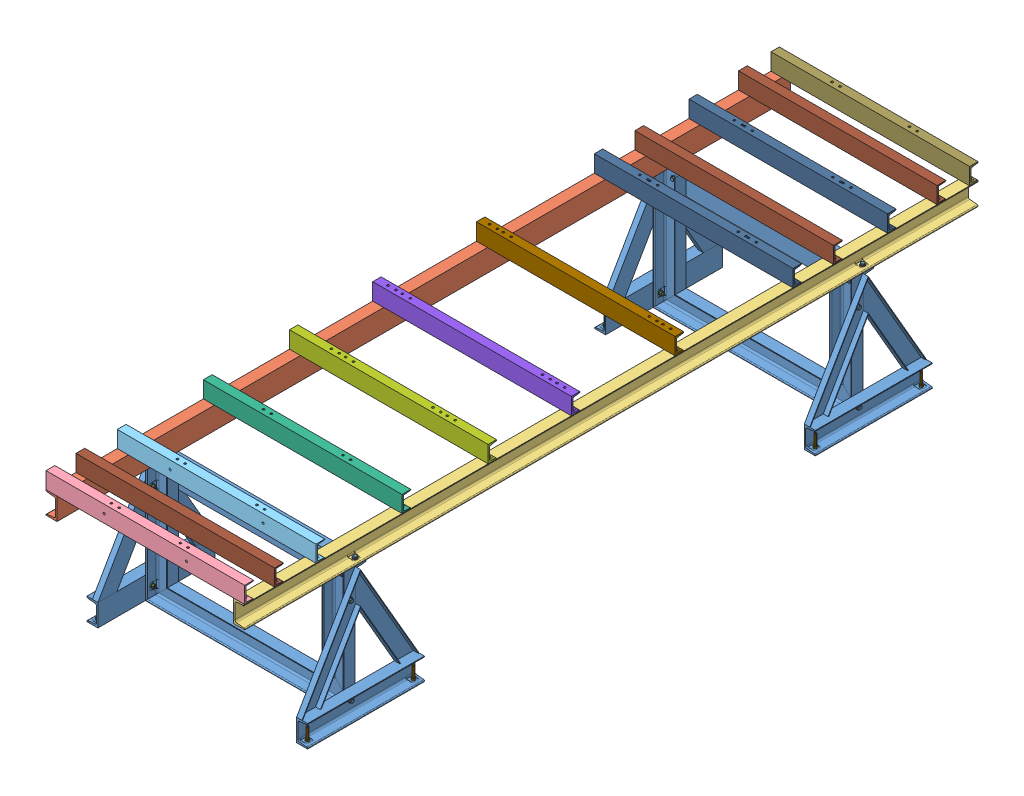
SolidWorks assembly MainJig, configuration Default. Lengths in mm.
Overall size (1000 753.95 3322.05).
208 component instances, 16 part files, 46 mates.
Components (placement in the parent):
- MainJigLegs-1: MainJigLegs [Default<As Machined>] at origin size (1000 560 530)
- MainJigLegs-2: MainJigLegs [Default<As Machined>] at (0 0 2300) size (1000 560 530)
- MainJigLongRailRight-1: MainJigLongRailRight [Default<As Machined>] at (-400 50 2270) x (0 0 -1) z (1 0 0) size (3322 100 50)
- MainJigLongRailLeft-1: MainJigLongRailLeft [Default<As Machined>] at (400 50 2270) x (0 0 -1) z (1 0 0) size (3322 100 50)
- MainJigCrossRailA-1: MainJigCrossRailA [Default<As Machined>] at (0 137.5 2800) size (900 75 40)
- MainJigCrossRailC-2: MainJigCrossRailC [Default<As Machined>] at (0 137.5 2477) size (900 75 40)
- MainJigCrossRailD-3: MainJigCrossRailD [Default<As Machined>] at (0 137.5 2087.1) size (900 75 40)
- MainJigCrossRailE-4: MainJigCrossRailE [Default<As Machined>] at (0 138.1 1697) size (900 76.2 38.05)
- MainJigCrossRailF-5: MainJigCrossRailF [Default<As Machined>] at (0 138.1 1320) size (900 76.2 38.05)
- MainJigCrossRailG-6: MainJigCrossRailG [Default<As Machined>] at (0 138.1 850) size (900 76.2 38.05)
- MainJigCrossRailH-7: MainJigCrossRailH [Default<As Machined>] at (0 138.1 316.2) size (900 76.2 38.05)
- MainJigCrossRail-8: MainJigCrossRail [Default<As Machined>] at (0 137.5 2664.3) size (900 75 40)
- MainJigCrossRail-9: MainJigCrossRail [Default<As Machined>] at (0 137.5 132.6) size (900 75 40)
- MainJigCrossRailH-10: MainJigCrossRailH [Default<As Machined>] at (0 138.1 -112.5) size (900 76.2 38.05)
- MainJigCrossRail-11: MainJigCrossRail [Default<As Machined>] at (0 137.5 -336.9) size (900 75 40)
- MainJigCrossRailL-12: MainJigCrossRailL [Default<As Machined>] at (0 138.1 -484) size (900 76.2 38.05)
- Flat Washer Type A Narrow_AI-36: Flat Washer Type A Narrow_AI [Preferred Narrow FW 0.375] at (425 105 2780) x (0 -1 0) z (0 0 1) size (1.65 20.62 20.62)
- Flat Washer Type A Narrow_AI-37: Flat Washer Type A Narrow_AI [Preferred Narrow FW 0.375] at (425 104 2457) x (0 -1 0) z (0 0 1) size (1.65 20.62 20.62)
- Flat Washer Type A Narrow_AI-38: Flat Washer Type A Narrow_AI [Preferred Narrow FW 0.375] at (425 105 2067.1) x (0 -1 0) z (0 0 1) size (1.65 20.62 20.62)
- Flat Washer Type A Narrow_AI-39: Flat Washer Type A Narrow_AI [Preferred Narrow FW 0.375] at (425 105 1677) x (0 -1 0) z (0 0 1) size (1.65 20.62 20.62)
- Flat Washer Type A Narrow_AI-40: Flat Washer Type A Narrow_AI [Preferred Narrow FW 0.375] at (425 105 1300) x (0 -1 0) z (0 0 1) size (1.65 20.62 20.62)
- Flat Washer Type A Narrow_AI-41: Flat Washer Type A Narrow_AI [Preferred Narrow FW 0.375] at (425 105 830) x (0 -1 0) z (0 0 1) size (1.65 20.62 20.62)
- Flat Washer Type A Narrow_AI-42: Flat Washer Type A Narrow_AI [Preferred Narrow FW 0.375] at (425 105 2644.3) x (0 -1 0) z (0 0 1) size (1.65 20.62 20.62)
- Flat Washer Type A Narrow_AI-43: Flat Washer Type A Narrow_AI [Preferred Narrow FW 0.375] at (425 105 296.2) x (0 -1 0) z (0 0 1) size (1.65 20.62 20.62)
- Flat Washer Type A Narrow_AI-44: Flat Washer Type A Narrow_AI [Preferred Narrow FW 0.375] at (425 104.6 112.6) x (0 -1 0) z (0 0 1) size (1.65 20.62 20.62)
- Flat Washer Type A Narrow_AI-45: Flat Washer Type A Narrow_AI [Preferred Narrow FW 0.375] at (425 105 -132.5) x (0 -1 0) z (0 0 1) size (1.65 20.62 20.62)
- Flat Washer Type A Narrow_AI-46: Flat Washer Type A Narrow_AI [Preferred Narrow FW 0.375] at (425 104 -356.9) x (0 -1 0) z (0 0 1) size (1.65 20.62 20.62)
- Flat Washer Type A Narrow_AI-48: Flat Washer Type A Narrow_AI [Preferred Narrow FW 0.375] at (425 105 -504) x (0 -1 0) z (0 0 1) size (1.65 20.62 20.62)
- Flat Washer Type A Narrow_AI-49: Flat Washer Type A Narrow_AI [Preferred Narrow FW 0.375] at (-425 105 2780) x (0 -1 0) z (0 0 1) size (1.65 20.62 20.62)
- Flat Washer Type A Narrow_AI-50: Flat Washer Type A Narrow_AI [Preferred Narrow FW 0.375] at (-425 105 2457) x (0 -1 0) z (0 0 1) size (1.65 20.62 20.62)
- Flat Washer Type A Narrow_AI-51: Flat Washer Type A Narrow_AI [Preferred Narrow FW 0.375] at (-425 105 2067.1) x (0 -1 0) z (0 0 1) size (1.65 20.62 20.62)
- Flat Washer Type A Narrow_AI-52: Flat Washer Type A Narrow_AI [Preferred Narrow FW 0.375] at (-425 105 1677) x (0 -1 0) z (0 0 1) size (1.65 20.62 20.62)
- Flat Washer Type A Narrow_AI-53: Flat Washer Type A Narrow_AI [Preferred Narrow FW 0.375] at (-425 105 1300) x (0 -1 0) z (0 0 1) size (1.65 20.62 20.62)
- Flat Washer Type A Narrow_AI-54: Flat Washer Type A Narrow_AI [Preferred Narrow FW 0.375] at (-425 105 830) x (0 -1 0) z (0 0 1) size (1.65 20.62 20.62)
- Flat Washer Type A Narrow_AI-56: Flat Washer Type A Narrow_AI [Preferred Narrow FW 0.375] at (-425 105 2644.3) x (0 -1 0) z (0 0 1) size (1.65 20.62 20.62)
- Flat Washer Type A Narrow_AI-57: Flat Washer Type A Narrow_AI [Preferred Narrow FW 0.375] at (-425 105 296.2) x (0 -1 0) z (0 0 1) size (1.65 20.62 20.62)
- Flat Washer Type A Narrow_AI-58: Flat Washer Type A Narrow_AI [Preferred Narrow FW 0.375] at (-425 104.6 112.6) x (0 -1 0) z (0 0 1) size (1.65 20.62 20.62)
- Flat Washer Type A Narrow_AI-59: Flat Washer Type A Narrow_AI [Preferred Narrow FW 0.375] at (-425 105 -132.5) x (0 -1 0) z (0 0 1) size (1.65 20.62 20.62)
- Flat Washer Type A Narrow_AI-60: Flat Washer Type A Narrow_AI [Preferred Narrow FW 0.375] at (-425 104 -356.9) x (0 -1 0) z (0 0 1) size (1.65 20.62 20.62)
- Flat Washer Type A Narrow_AI-61: Flat Washer Type A Narrow_AI [Preferred Narrow FW 0.375] at (-425 105 -504) x (0 -1 0) z (0 0 1) size (1.65 20.62 20.62)
- Hex Bolt_AI-17: Hex Bolt_AI [HBOLT 0.3750-16x1.25x1-N] at (425 113.4582 2780) x (0 -1 0) z (0 0 1) size (38.56 16.48 14.27)
- Hex Bolt_AI-18: Hex Bolt_AI [HBOLT 0.3750-16x1.25x1-N] at (425 112.4582 2457) x (0 -1 0) z (0 0 1) size (38.56 16.48 14.27)
- Hex Bolt_AI-19: Hex Bolt_AI [HBOLT 0.3750-16x1.25x1-N] at (425 113.4582 2067.1) x (0 -1 0) z (0 0 1) size (38.56 16.48 14.27)
- Hex Bolt_AI-20: Hex Bolt_AI [HBOLT 0.3750-16x1.25x1-N] at (425 113.4582 1677) x (0 -1 0) z (0 0 1) size (38.56 16.48 14.27)
- Hex Bolt_AI-21: Hex Bolt_AI [HBOLT 0.3750-16x1.25x1-N] at (425 113.4582 1300) x (0 -1 0) z (0 0 1) size (38.56 16.48 14.27)
- Hex Bolt_AI-22: Hex Bolt_AI [HBOLT 0.3750-16x1.25x1-N] at (425 113.4582 830) x (0 -1 0) z (0 0 1) size (38.56 16.48 14.27)
- Hex Bolt_AI-23: Hex Bolt_AI [HBOLT 0.3750-16x1.25x1-N] at (425 113.4582 2644.3) x (0 -1 0) z (0 0 1) size (38.56 16.48 14.27)
- Hex Bolt_AI-24: Hex Bolt_AI [HBOLT 0.3750-16x1.25x1-N] at (425 113.4582 296.2) x (0 -1 0) z (0 0 1) size (38.56 16.48 14.27)
- Hex Bolt_AI-25: Hex Bolt_AI [HBOLT 0.3750-16x1.25x1-N] at (425 113.0582 112.6) x (0 -1 0) z (0 0 1) size (38.56 16.48 14.27)
- Hex Bolt_AI-26: Hex Bolt_AI [HBOLT 0.3750-16x1.25x1-N] at (425 113.4582 -132.5) x (0 -1 0) z (0 0 1) size (38.56 16.48 14.27)
- Hex Bolt_AI-27: Hex Bolt_AI [HBOLT 0.3750-16x1.25x1-N] at (425 112.4582 -356.9) x (0 -1 0) z (0 0 1) size (38.56 16.48 14.27)
- Hex Bolt_AI-28: Hex Bolt_AI [HBOLT 0.3750-16x1.25x1-N] at (425 113.4582 -504) x (0 -1 0) z (0 0 1) size (38.56 16.48 14.27)
- Hex Bolt_AI-29: Hex Bolt_AI [HBOLT 0.3750-16x1.25x1-N] at (-425 113.4582 2780) x (0 -1 0) z (0 0 1) size (38.56 16.48 14.27)
- Hex Bolt_AI-30: Hex Bolt_AI [HBOLT 0.3750-16x1.25x1-N] at (-425 113.4582 2457) x (0 -1 0) z (0 0 1) size (38.56 16.48 14.27)
- Hex Bolt_AI-31: Hex Bolt_AI [HBOLT 0.3750-16x1.25x1-N] at (-425 113.4582 2067.1) x (0 -1 0) z (0 0 1) size (38.56 16.48 14.27)
- Hex Bolt_AI-32: Hex Bolt_AI [HBOLT 0.3750-16x1.25x1-N] at (-425 113.4582 1677) x (0 -1 0) z (0 0 1) size (38.56 16.48 14.27)
- Hex Bolt_AI-33: Hex Bolt_AI [HBOLT 0.3750-16x1.25x1-N] at (-425 113.4582 1300) x (0 -1 0) z (0 0 1) size (38.56 16.48 14.27)
- Hex Bolt_AI-34: Hex Bolt_AI [HBOLT 0.3750-16x1.25x1-N] at (-425 113.4582 830) x (0 -1 0) z (0 0 1) size (38.56 16.48 14.27)
- Hex Bolt_AI-35: Hex Bolt_AI [HBOLT 0.3750-16x1.25x1-N] at (-425 113.4582 2644.3) x (0 -1 0) z (0 0 1) size (38.56 16.48 14.27)
- Hex Bolt_AI-36: Hex Bolt_AI [HBOLT 0.3750-16x1.25x1-N] at (-425 113.4582 296.2) x (0 -1 0) z (0 0 1) size (38.56 16.48 14.27)
- Hex Bolt_AI-37: Hex Bolt_AI [HBOLT 0.3750-16x1.25x1-N] at (-425 113.0582 112.6) x (0 -1 0) z (0 0 1) size (38.56 16.48 14.27)
- Hex Bolt_AI-38: Hex Bolt_AI [HBOLT 0.3750-16x1.25x1-N] at (-425 113.4582 -132.5) x (0 -1 0) z (0 0 1) size (38.56 16.48 14.27)
- Hex Bolt_AI-39: Hex Bolt_AI [HBOLT 0.3750-16x1.25x1-N] at (-425 112.4582 -356.9) x (0 -1 0) z (0 0 1) size (38.56 16.48 14.27)
- Hex Bolt_AI-40: Hex Bolt_AI [HBOLT 0.3750-16x1.25x1-N] at (-425 113.4582 -504) x (0 -1 0) z (0 0 1) size (38.56 16.48 14.27)
- Lock Washer Spring Regular_AI-68: Lock Washer Spring Regular_AI [Regular LW 0.375] at (425 93 2780) x (0 1 0) z (0 0 1) size (2.39 17.35 17.32)
- Lock Washer Spring Regular_AI-69: Lock Washer Spring Regular_AI [Regular LW 0.375] at (425 93 2644.3) x (0 1 0) z (0 0 1) size (2.39 17.35 17.32)
- Lock Washer Spring Regular_AI-70: Lock Washer Spring Regular_AI [Regular LW 0.375] at (425 93 2457) x (0 1 0) z (0 0 1) size (2.39 17.35 17.32)
- Lock Washer Spring Regular_AI-71: Lock Washer Spring Regular_AI [Regular LW 0.375] at (425 93 2067.1) x (0 1 0) z (0 0 1) size (2.39 17.35 17.32)
- Lock Washer Spring Regular_AI-72: Lock Washer Spring Regular_AI [Regular LW 0.375] at (425 93 1677) x (0 1 0) z (0 0 1) size (2.39 17.35 17.32)
- Lock Washer Spring Regular_AI-73: Lock Washer Spring Regular_AI [Regular LW 0.375] at (425 93 1300) x (0 1 0) z (0 0 1) size (2.39 17.35 17.32)
- Lock Washer Spring Regular_AI-74: Lock Washer Spring Regular_AI [Regular LW 0.375] at (425 93 830) x (0 1 0) z (0 0 1) size (2.39 17.35 17.32)
- Lock Washer Spring Regular_AI-75: Lock Washer Spring Regular_AI [Regular LW 0.375] at (425 93 296.2) x (0 1 0) z (0 0 1) size (2.39 17.35 17.32)
- Lock Washer Spring Regular_AI-76: Lock Washer Spring Regular_AI [Regular LW 0.375] at (425 93 112.6) x (0 1 0) z (0 0 1) size (2.39 17.35 17.32)
- Lock Washer Spring Regular_AI-78: Lock Washer Spring Regular_AI [Regular LW 0.375] at (425 93 -132.5) x (0 1 0) z (0 0 1) size (2.39 17.35 17.32)
- Lock Washer Spring Regular_AI-79: Lock Washer Spring Regular_AI [Regular LW 0.375] at (425 93 -356.9) x (0 1 0) z (0 0 1) size (2.39 17.35 17.32)
- Lock Washer Spring Regular_AI-80: Lock Washer Spring Regular_AI [Regular LW 0.375] at (425 93 -504) x (0 1 0) z (0 0 1) size (2.39 17.35 17.32)
- Lock Washer Spring Regular_AI-81: Lock Washer Spring Regular_AI [Regular LW 0.375] at (-425 93 2780) x (0 1 0) z (0 0 1) size (2.39 17.35 17.32)
- Lock Washer Spring Regular_AI-82: Lock Washer Spring Regular_AI [Regular LW 0.375] at (-425 93 2644.3) x (0 1 0) z (0 0 1) size (2.39 17.35 17.32)
- Lock Washer Spring Regular_AI-83: Lock Washer Spring Regular_AI [Regular LW 0.375] at (-425 93 2457) x (0 1 0) z (0 0 1) size (2.39 17.35 17.32)
- Lock Washer Spring Regular_AI-84: Lock Washer Spring Regular_AI [Regular LW 0.375] at (-425 93 2067.1) x (0 1 0) z (0 0 1) size (2.39 17.35 17.32)
- Lock Washer Spring Regular_AI-85: Lock Washer Spring Regular_AI [Regular LW 0.375] at (-425 93 1677) x (0 1 0) z (0 0 1) size (2.39 17.35 17.32)
- Lock Washer Spring Regular_AI-86: Lock Washer Spring Regular_AI [Regular LW 0.375] at (-425 93 1300) x (0 1 0) z (0 0 1) size (2.39 17.35 17.32)
- Lock Washer Spring Regular_AI-87: Lock Washer Spring Regular_AI [Regular LW 0.375] at (-425 93 830) x (0 1 0) z (0 0 1) size (2.39 17.35 17.32)
- Lock Washer Spring Regular_AI-88: Lock Washer Spring Regular_AI [Regular LW 0.375] at (-425 93 296.2) x (0 1 0) z (0 0 1) size (2.39 17.35 17.32)
- Lock Washer Spring Regular_AI-89: Lock Washer Spring Regular_AI [Regular LW 0.375] at (-425 93 112.6) x (0 1 0) z (0 0 1) size (2.39 17.35 17.32)
- Lock Washer Spring Regular_AI-90: Lock Washer Spring Regular_AI [Regular LW 0.375] at (-425 93 -132.5) x (0 1 0) z (0 0 1) size (2.39 17.35 17.32)
- Lock Washer Spring Regular_AI-91: Lock Washer Spring Regular_AI [Regular LW 0.375] at (-425 93 -356.9) x (0 1 0) z (0 0 1) size (2.39 17.35 17.32)
- Lock Washer Spring Regular_AI-92: Lock Washer Spring Regular_AI [Regular LW 0.375] at (-425 93 -504) x (0 1 0) z (0 0 1) size (2.39 17.35 17.32)
- Hex Nut_AI-92: Hex Nut_AI [HNUT 0.3750-16-D-N] at (425 82.0526 2780) x (1 0 0) z (0 -1 0) size (14.27 16.48 8.56)
- Hex Nut_AI-93: Hex Nut_AI [HNUT 0.3750-16-D-N] at (425 82.0526 2644.3) x (1 0 0) z (0 -1 0) size (14.27 16.48 8.56)
- Hex Nut_AI-94: Hex Nut_AI [HNUT 0.3750-16-D-N] at (425 82.0526 2457) x (1 0 0) z (0 -1 0) size (14.27 16.48 8.56)
- Hex Nut_AI-95: Hex Nut_AI [HNUT 0.3750-16-D-N] at (425 82.0526 2067.1) x (1 0 0) z (0 -1 0) size (14.27 16.48 8.56)
- Hex Nut_AI-96: Hex Nut_AI [HNUT 0.3750-16-D-N] at (425 82.0526 1677) x (1 0 0) z (0 -1 0) size (14.27 16.48 8.56)
- Hex Nut_AI-97: Hex Nut_AI [HNUT 0.3750-16-D-N] at (425 82.0526 1300) x (1 0 0) z (0 -1 0) size (14.27 16.48 8.56)
- Hex Nut_AI-98: Hex Nut_AI [HNUT 0.3750-16-D-N] at (425 82.0526 830) x (1 0 0) z (0 -1 0) size (14.27 16.48 8.56)
- Hex Nut_AI-99: Hex Nut_AI [HNUT 0.3750-16-D-N] at (425 82.0526 296.2) x (1 0 0) z (0 -1 0) size (14.27 16.48 8.56)
- Hex Nut_AI-100: Hex Nut_AI [HNUT 0.3750-16-D-N] at (425 82.0526 112.6) x (1 0 0) z (0 -1 0) size (14.27 16.48 8.56)
- Hex Nut_AI-101: Hex Nut_AI [HNUT 0.3750-16-D-N] at (425 82.0526 -132.5) x (1 0 0) z (0 -1 0) size (14.27 16.48 8.56)
- Hex Nut_AI-102: Hex Nut_AI [HNUT 0.3750-16-D-N] at (425 82.0526 -356.9) x (1 0 0) z (0 -1 0) size (14.27 16.48 8.56)
- Hex Nut_AI-103: Hex Nut_AI [HNUT 0.3750-16-D-N] at (425 82.0526 -504) x (1 0 0) z (0 -1 0) size (14.27 16.48 8.56)
- Hex Nut_AI-104: Hex Nut_AI [HNUT 0.3750-16-D-N] at (-425 82.0526 2780) x (1 0 0) z (0 -1 0) size (14.27 16.48 8.56)
- Hex Nut_AI-105: Hex Nut_AI [HNUT 0.3750-16-D-N] at (-425 82.0526 2644.3) x (1 0 0) z (0 -1 0) size (14.27 16.48 8.56)
- Hex Nut_AI-106: Hex Nut_AI [HNUT 0.3750-16-D-N] at (-425 82.0526 2457) x (1 0 0) z (0 -1 0) size (14.27 16.48 8.56)
- Hex Nut_AI-107: Hex Nut_AI [HNUT 0.3750-16-D-N] at (-425 82.0526 2067.1) x (1 0 0) z (0 -1 0) size (14.27 16.48 8.56)
- Hex Nut_AI-108: Hex Nut_AI [HNUT 0.3750-16-D-N] at (-425 82.0526 1677) x (1 0 0) z (0 -1 0) size (14.27 16.48 8.56)
- Hex Nut_AI-109: Hex Nut_AI [HNUT 0.3750-16-D-N] at (-425 82.0526 1300) x (1 0 0) z (0 -1 0) size (14.27 16.48 8.56)
- Hex Nut_AI-110: Hex Nut_AI [HNUT 0.3750-16-D-N] at (-425 82.0526 830) x (1 0 0) z (0 -1 0) size (14.27 16.48 8.56)
- Hex Nut_AI-111: Hex Nut_AI [HNUT 0.3750-16-D-N] at (-425 82.0526 296.2) x (1 0 0) z (0 -1 0) size (14.27 16.48 8.56)
- Hex Nut_AI-112: Hex Nut_AI [HNUT 0.3750-16-D-N] at (-425 82.0526 112.6) x (1 0 0) z (0 -1 0) size (14.27 16.48 8.56)
- Hex Nut_AI-113: Hex Nut_AI [HNUT 0.3750-16-D-N] at (-425 82.0526 -132.5) x (1 0 0) z (0 -1 0) size (14.27 16.48 8.56)
- Hex Nut_AI-114: Hex Nut_AI [HNUT 0.3750-16-D-N] at (-425 82.0526 -356.9) x (1 0 0) z (0 -1 0) size (14.27 16.48 8.56)
- Hex Nut_AI-115: Hex Nut_AI [HNUT 0.3750-16-D-N] at (-425 82.0526 -504) x (1 0 0) z (0 -1 0) size (14.27 16.48 8.56)
- Flat Washer Type A Narrow_AI-62: Flat Washer Type A Narrow_AI [Preferred Narrow FW 0.375] at (-453 -119.3078 25) size (1.65 20.62 20.62)
- Flat Washer Type A Narrow_AI-63: Flat Washer Type A Narrow_AI [Preferred Narrow FW 0.375] at (-455.9 -510 25) size (1.65 20.62 20.62)
- Flat Washer Type A Narrow_AI-64: Flat Washer Type A Narrow_AI [Preferred Narrow FW 0.375] at (453 -119.3078 25) x (-1 0 0) z (0 0.924225 0.381849) size (1.65 20.62 20.62)
- Flat Washer Type A Narrow_AI-65: Flat Washer Type A Narrow_AI [Preferred Narrow FW 0.375] at (455.9 -510 25) x (-1 0 0) z (0 0.924225 0.381849) size (1.65 20.62 20.62)
- Flat Washer Type A Narrow_AI-66: Flat Washer Type A Narrow_AI [Preferred Narrow FW 0.375] at (453 -119.3078 2325) x (-1 0 0) z (0 0.924225 0.381849) size (1.65 20.62 20.62)
- Flat Washer Type A Narrow_AI-67: Flat Washer Type A Narrow_AI [Preferred Narrow FW 0.375] at (455.9 -510 2325) x (-1 0 0) z (0 0.924225 0.381849) size (1.65 20.62 20.62)
- Flat Washer Type A Narrow_AI-68: Flat Washer Type A Narrow_AI [Preferred Narrow FW 0.375] at (-453 -119.3078 2325) size (1.65 20.62 20.62)
- Flat Washer Type A Narrow_AI-69: Flat Washer Type A Narrow_AI [Preferred Narrow FW 0.375] at (-455.9 -510 2325) size (1.65 20.62 20.62)
- Flat Washer Type A Narrow_AI-70: Flat Washer Type A Narrow_AI [Preferred Narrow FW 0.375] at (-400 -50 2305.9) x (0 0 -1) z (1 0 0) size (1.65 20.62 20.62)
- Flat Washer Type A Narrow_AI-71: Flat Washer Type A Narrow_AI [Preferred Narrow FW 0.375] at (400 -50 2305.9) x (0 0 -1) z (1 0 0) size (1.65 20.62 20.62)
- Flat Washer Type A Narrow_AI-72: Flat Washer Type A Narrow_AI [Preferred Narrow FW 0.375] at (-400 -50 5.9) x (0 0 -1) z (1 0 0) size (1.65 20.62 20.62)
- Flat Washer Type A Narrow_AI-73: Flat Washer Type A Narrow_AI [Preferred Narrow FW 0.375] at (400 -50 5.9) x (0 0 -1) z (1 0 0) size (1.65 20.62 20.62)
- Flat Washer Type A Narrow_AI-74: Flat Washer Type A Narrow_AI [Preferred Narrow FW 0.375] at (425 7 2275) x (0 -1 0) z (0 0 1) size (1.65 20.62 20.62)
- Flat Washer Type A Narrow_AI-75: Flat Washer Type A Narrow_AI [Preferred Narrow FW 0.375] at (425 7 -25) x (0 -1 0) z (0 0 1) size (1.65 20.62 20.62)
- Flat Washer Type A Narrow_AI-76: Flat Washer Type A Narrow_AI [Preferred Narrow FW 0.375] at (-425 7 -25) x (0 -1 0) z (0 0 1) size (1.65 20.62 20.62)
- Flat Washer Type A Narrow_AI-77: Flat Washer Type A Narrow_AI [Preferred Narrow FW 0.375] at (-425 7 2275) x (0 -1 0) z (0 0 1) size (1.65 20.62 20.62)
- Lock Washer Spring Regular_AI-93: Lock Washer Spring Regular_AI [Regular LW 0.375] at (-425 -6.4843 2275) x (0 1 0) z (0 0 1) size (2.39 17.35 17.32)
- Lock Washer Spring Regular_AI-94: Lock Washer Spring Regular_AI [Regular LW 0.375] at (-400 -50 2294.1) x (0 0 1) z (-1 0 0) size (2.39 17.35 17.32)
- Lock Washer Spring Regular_AI-95: Lock Washer Spring Regular_AI [Regular LW 0.375] at (400 -50 2294.1) x (0 0 1) z (-1 0 0) size (2.39 17.35 17.32)
- Lock Washer Spring Regular_AI-96: Lock Washer Spring Regular_AI [Regular LW 0.375] at (425 -6.4843 2275) x (0 1 0) z (0 0 1) size (2.39 17.35 17.32)
- Lock Washer Spring Regular_AI-97: Lock Washer Spring Regular_AI [Regular LW 0.375] at (443 -119.3078 2325) size (2.39 17.35 17.32)
- Lock Washer Spring Regular_AI-98: Lock Washer Spring Regular_AI [Regular LW 0.375] at (443 -510 2325) size (2.39 17.35 17.32)
- Lock Washer Spring Regular_AI-99: Lock Washer Spring Regular_AI [Regular LW 0.375] at (-443 -119.3078 2325) x (-1 0 0) z (0 0.924225 0.381849) size (2.39 17.35 17.32)
- Lock Washer Spring Regular_AI-100: Lock Washer Spring Regular_AI [Regular LW 0.375] at (-443 -510 2325) x (-1 0 0) z (0 0.924225 0.381849) size (2.39 17.35 17.32)
- Lock Washer Spring Regular_AI-101: Lock Washer Spring Regular_AI [Regular LW 0.375] at (-475 -560 2540) x (0 1 0) z (0 0 1) size (2.39 17.35 17.32)
- Lock Washer Spring Regular_AI-102: Lock Washer Spring Regular_AI [Regular LW 0.375] at (-475 -560 2060) x (0 1 0) z (0 0 1) size (2.39 17.35 17.32)
- Lock Washer Spring Regular_AI-103: Lock Washer Spring Regular_AI [Regular LW 0.375] at (475 -560 2060) x (0 1 0) z (0 0 1) size (2.39 17.35 17.32)
- Lock Washer Spring Regular_AI-104: Lock Washer Spring Regular_AI [Regular LW 0.375] at (475 -560 2540) x (0 1 0) z (0 0 1) size (2.39 17.35 17.32)
- Lock Washer Spring Regular_AI-105: Lock Washer Spring Regular_AI [Regular LW 0.375] at (425 -6.4843 -25) x (0 1 0) z (0 0 1) size (2.39 17.35 17.32)
- Lock Washer Spring Regular_AI-106: Lock Washer Spring Regular_AI [Regular LW 0.375] at (400 -50 -5.9) x (0 0 1) z (-1 0 0) size (2.39 17.35 17.32)
- Lock Washer Spring Regular_AI-107: Lock Washer Spring Regular_AI [Regular LW 0.375] at (-400 -50 -5.9) x (0 0 1) z (-1 0 0) size (2.39 17.35 17.32)
- Lock Washer Spring Regular_AI-108: Lock Washer Spring Regular_AI [Regular LW 0.375] at (-425 -6.4843 -25) x (0 1 0) z (0 0 1) size (2.39 17.35 17.32)
- Lock Washer Spring Regular_AI-109: Lock Washer Spring Regular_AI [Regular LW 0.375] at (-443 -119.3078 25) x (-1 0 0) z (0 0.924225 0.381849) size (2.39 17.35 17.32)
- Lock Washer Spring Regular_AI-110: Lock Washer Spring Regular_AI [Regular LW 0.375] at (-443 -510 25) x (-1 0 0) z (0 0.924225 0.381849) size (2.39 17.35 17.32)
- Lock Washer Spring Regular_AI-111: Lock Washer Spring Regular_AI [Regular LW 0.375] at (443 -119.3078 25) size (2.39 17.35 17.32)
- Lock Washer Spring Regular_AI-112: Lock Washer Spring Regular_AI [Regular LW 0.375] at (443 -510 25) size (2.39 17.35 17.32)
- Lock Washer Spring Regular_AI-113: Lock Washer Spring Regular_AI [Regular LW 0.375] at (-475 -560 -240) x (0 1 0) z (0 0 1) size (2.39 17.35 17.32)
- Lock Washer Spring Regular_AI-114: Lock Washer Spring Regular_AI [Regular LW 0.375] at (-475 -560 240) x (0 1 0) z (0 0 1) size (2.39 17.35 17.32)
- Lock Washer Spring Regular_AI-115: Lock Washer Spring Regular_AI [Regular LW 0.375] at (475 -560 240) x (0 1 0) z (0 0 1) size (2.39 17.35 17.32)
- Lock Washer Spring Regular_AI-116: Lock Washer Spring Regular_AI [Regular LW 0.375] at (475 -560 -240) x (0 1 0) z (0 0 1) size (2.39 17.35 17.32)
- Hex Nut_AI-116: Hex Nut_AI [HNUT 0.3750-16-D-N] at (425 -17.4317 -25) x (1 0 0) z (0 -1 0) size (14.27 16.48 8.56)
- Hex Nut_AI-117: Hex Nut_AI [HNUT 0.3750-16-D-N] at (400 -50 -16.8474) x (0.923728 0.383049 0) z (0 0 -1) size (14.27 16.48 8.56)
- Hex Nut_AI-118: Hex Nut_AI [HNUT 0.3750-16-D-N] at (-425 -17.4317 -25) x (1 0 0) z (0 -1 0) size (14.27 16.48 8.56)
- Hex Nut_AI-119: Hex Nut_AI [HNUT 0.3750-16-D-N] at (-400 -50 -16.8474) x (0.923728 0.383049 0) z (0 0 -1) size (14.27 16.48 8.56)
- Hex Nut_AI-120: Hex Nut_AI [HNUT 0.3750-16-D-N] at (432.0526 -119.3078 25) x (0 0 1) z (-1 0 0) size (14.27 16.48 8.56)
- Hex Nut_AI-121: Hex Nut_AI [HNUT 0.3750-16-D-N] at (432.0526 -510 25) x (0 0 1) z (-1 0 0) size (14.27 16.48 8.56)
- Hex Nut_AI-122: Hex Nut_AI [HNUT 0.3750-16-D-N] at (-432.0526 -119.3078 25) x (0 0 -1) z (1 0 0) size (14.27 16.48 8.56)
- Hex Nut_AI-123: Hex Nut_AI [HNUT 0.3750-16-D-N] at (-432.0526 -510 25) x (0 0 -1) z (1 0 0) size (14.27 16.48 8.56)
- Hex Nut_AI-124: Hex Nut_AI [HNUT 0.3750-16-D-N] at (475 -570.9474 240) x (1 0 0) z (0 -1 0) size (14.27 16.48 8.56)
- Hex Nut_AI-125: Hex Nut_AI [HNUT 0.3750-16-D-N] at (475 -570.9474 -240) x (1 0 0) z (0 -1 0) size (14.27 16.48 8.56)
- Hex Nut_AI-126: Hex Nut_AI [HNUT 0.3750-16-D-N] at (-475 -570.9474 -240) x (1 0 0) z (0 -1 0) size (14.27 16.48 8.56)
- Hex Nut_AI-127: Hex Nut_AI [HNUT 0.3750-16-D-N] at (-475 -570.9474 240) x (1 0 0) z (0 -1 0) size (14.27 16.48 8.56)
- Hex Nut_AI-128: Hex Nut_AI [HNUT 0.3750-16-D-N] at (475 -544.4402 240) x (1 0 0) z (0 1 0) size (14.27 16.48 8.56)
- Hex Nut_AI-129: Hex Nut_AI [HNUT 0.3750-16-D-N] at (475 -544.4402 -240) x (1 0 0) z (0 1 0) size (14.27 16.48 8.56)
- Hex Nut_AI-130: Hex Nut_AI [HNUT 0.3750-16-D-N] at (-475 -544.4402 -240) x (1 0 0) z (0 1 0) size (14.27 16.48 8.56)
- Hex Nut_AI-131: Hex Nut_AI [HNUT 0.3750-16-D-N] at (-475 -544.4402 240) x (1 0 0) z (0 1 0) size (14.27 16.48 8.56)
- Hex Nut_AI-132: Hex Nut_AI [HNUT 0.3750-16-D-N] at (425 -17.4317 2275) x (1 0 0) z (0 -1 0) size (14.27 16.48 8.56)
- Hex Nut_AI-133: Hex Nut_AI [HNUT 0.3750-16-D-N] at (400 -50 2283.1526) x (0.923728 0.383049 0) z (0 0 -1) size (14.27 16.48 8.56)
- Hex Nut_AI-134: Hex Nut_AI [HNUT 0.3750-16-D-N] at (-425 -17.4317 2275) x (1 0 0) z (0 -1 0) size (14.27 16.48 8.56)
- Hex Nut_AI-135: Hex Nut_AI [HNUT 0.3750-16-D-N] at (-400 -50 2283.1526) x (0.923728 0.383049 0) z (0 0 -1) size (14.27 16.48 8.56)
- Hex Nut_AI-136: Hex Nut_AI [HNUT 0.3750-16-D-N] at (-432.0526 -119.3078 2325) x (0 0 -1) z (1 0 0) size (14.27 16.48 8.56)
- Hex Nut_AI-137: Hex Nut_AI [HNUT 0.3750-16-D-N] at (-432.0526 -510 2325) x (0 0 -1) z (1 0 0) size (14.27 16.48 8.56)
- Hex Nut_AI-138: Hex Nut_AI [HNUT 0.3750-16-D-N] at (432.0526 -510 2325) x (0 0 1) z (-1 0 0) size (14.27 16.48 8.56)
- Hex Nut_AI-139: Hex Nut_AI [HNUT 0.3750-16-D-N] at (432.0526 -119.3078 2325) x (0 0 1) z (-1 0 0) size (14.27 16.48 8.56)
- Hex Nut_AI-140: Hex Nut_AI [HNUT 0.3750-16-D-N] at (-475 -570.9474 2060) x (1 0 0) z (0 -1 0) size (14.27 16.48 8.56)
- Hex Nut_AI-141: Hex Nut_AI [HNUT 0.3750-16-D-N] at (-475 -570.9474 2540) x (1 0 0) z (0 -1 0) size (14.27 16.48 8.56)
- Hex Nut_AI-142: Hex Nut_AI [HNUT 0.3750-16-D-N] at (475 -570.9474 2540) x (1 0 0) z (0 -1 0) size (14.27 16.48 8.56)
- Hex Nut_AI-143: Hex Nut_AI [HNUT 0.3750-16-D-N] at (475 -570.9474 2060) x (1 0 0) z (0 -1 0) size (14.27 16.48 8.56)
- Hex Nut_AI-144: Hex Nut_AI [HNUT 0.3750-16-D-N] at (-475 -544.4402 2060) x (1 0 0) z (0 1 0) size (14.27 16.48 8.56)
- Hex Nut_AI-145: Hex Nut_AI [HNUT 0.3750-16-D-N] at (-475 -544.4402 2540) x (1 0 0) z (0 1 0) size (14.27 16.48 8.56)
- Hex Nut_AI-146: Hex Nut_AI [HNUT 0.3750-16-D-N] at (475 -544.4402 2540) x (1 0 0) z (0 1 0) size (14.27 16.48 8.56)
- Hex Nut_AI-147: Hex Nut_AI [HNUT 0.3750-16-D-N] at (475 -544.4402 2060) x (1 0 0) z (0 1 0) size (14.27 16.48 8.56)
- Hex Bolt_AI-41: Hex Bolt_AI [HBOLT 0.3750-16x1.25x1-N] at (425 15.4582 -25) x (0 -1 0) z (0 0 1) size (38.56 16.48 14.27)
- Hex Bolt_AI-42: Hex Bolt_AI [HBOLT 0.3750-16x1.25x1-N] at (400 -50 14.3582) x (0 0 -1) z (1 0 0) size (38.56 16.48 14.27)
- Hex Bolt_AI-43: Hex Bolt_AI [HBOLT 0.3750-16x1.25x1-N] at (461.4582 -119.3078 25) x (-1 0 0) z (0 0.924225 0.381849) size (38.56 16.48 14.27)
- Hex Bolt_AI-44: Hex Bolt_AI [HBOLT 0.3750-16x1.25x1-N] at (464.3582 -510 25) x (-1 0 0) z (0 0.924225 0.381849) size (38.56 16.48 14.27)
- Hex Bolt_AI-45: Hex Bolt_AI [HBOLT 0.3750-16x1.25x1-N] at (-400 -50 14.3582) x (0 0 -1) z (1 0 0) size (38.56 16.48 14.27)
- Hex Bolt_AI-46: Hex Bolt_AI [HBOLT 0.3750-16x1.25x1-N] at (-461.4582 -119.3078 25) size (38.56 16.48 14.27)
- Hex Bolt_AI-47: Hex Bolt_AI [HBOLT 0.3750-16x1.25x1-N] at (-464.3582 -510 25) size (38.56 16.48 14.27)
- Hex Bolt_AI-48: Hex Bolt_AI [HBOLT 0.3750-16x1.25x1-N] at (-425 15.4582 -25) x (0 -1 0) z (0 0 1) size (38.56 16.48 14.27)
- Hex Bolt_AI-49: Hex Bolt_AI [HBOLT 0.3750-16x1.25x1-N] at (425 15.4582 2275) x (0 -1 0) z (0 0 1) size (38.56 16.48 14.27)
- Hex Bolt_AI-50: Hex Bolt_AI [HBOLT 0.3750-16x1.25x1-N] at (461.4582 -119.3078 2325) x (-1 0 0) z (0 0.924225 0.381849) size (38.56 16.48 14.27)
- Hex Bolt_AI-52: Hex Bolt_AI [HBOLT 0.3750-16x1.25x1-N] at (464.3582 -510 2325) x (-1 0 0) z (0 0.924225 0.381849) size (38.56 16.48 14.27)
- Hex Bolt_AI-53: Hex Bolt_AI [HBOLT 0.3750-16x1.125x1-N] at (400 -50 2314.3582) x (0 0 -1) z (1 0 0) size (35.38 16.48 14.27)
- Hex Bolt_AI-54: Hex Bolt_AI [HBOLT 0.3750-16x1.125x1-N] at (-400 -50 2314.3582) x (0 0 -1) z (1 0 0) size (35.38 16.48 14.27)
- Hex Bolt_AI-55: Hex Bolt_AI [HBOLT 0.3750-16x1.125x1-N] at (-461.4582 -119.3078 2325) size (35.38 16.48 14.27)
- Hex Bolt_AI-56: Hex Bolt_AI [HBOLT 0.3750-16x1.125x1-N] at (-464.3582 -510 2325) size (35.38 16.48 14.27)
- Hex Bolt_AI-57: Hex Bolt_AI [HBOLT 0.3750-16x1.125x1-N] at (-425 15.4582 2275) x (0 -1 0) z (0 0 1) size (35.38 16.48 14.27)
- Hex Bolt_AI-58: Hex Bolt_AI [HBOLT 0.3750-16x3x1-N] at (475 -577.7546 2540) x (0 1 0) z (0 0 1) size (83.01 16.48 14.27)
- Hex Bolt_AI-59: Hex Bolt_AI [HBOLT 0.3750-16x3x1-N] at (475 -577.7546 2060) x (0 1 0) z (0 0 1) size (83.01 16.48 14.27)
- Hex Bolt_AI-60: Hex Bolt_AI [HBOLT 0.3750-16x3x1-N] at (-475 -577.7546 2540) x (0 1 0) z (0 0 1) size (83.01 16.48 14.27)
- Hex Bolt_AI-61: Hex Bolt_AI [HBOLT 0.3750-16x3x1-N] at (-475 -577.7546 2060) x (0 1 0) z (0 0 1) size (83.01 16.48 14.27)
- Hex Bolt_AI-62: Hex Bolt_AI [HBOLT 0.3750-16x3x1-N] at (-475 -577.7546 240) x (0 1 0) z (0 0 1) size (83.01 16.48 14.27)
- Hex Bolt_AI-63: Hex Bolt_AI [HBOLT 0.3750-16x3x1-N] at (-475 -577.7546 -240) x (0 1 0) z (0 0 1) size (83.01 16.48 14.27)
- Hex Bolt_AI-64: Hex Bolt_AI [HBOLT 0.3750-16x3x1-N] at (475 -577.7546 240) x (0 1 0) z (0 0 1) size (83.01 16.48 14.27)
- Hex Bolt_AI-65: Hex Bolt_AI [HBOLT 0.3750-16x3x1-N] at (475 -577.7546 -240) x (0 1 0) z (0 0 1) size (83.01 16.48 14.27)
Mates (geometry in assembly coordinates):
- Parallel1: parallel: plane of assembly through (0 0 0) normal (1 0 0); plane of MainJigLongRailRight-1 through (-400 50 2270) normal (1 0 0); plane of assembly
- Coincident105: coincident: plane of assembly through (0 0 0) normal (1 0 0); plane of MainJigCrossRailA-1 through (0 137.5 2800) normal (1 0 0); plane of assembly
- Coincident108: coincident: plane of assembly through (0 0 0) normal (1 0 0); plane of MainJigCrossRailC-2 through (0 137.5 2477) normal (1 0 0); plane of assembly
- Coincident109: coincident: plane of assembly through (0 0 0) normal (1 0 0); plane of MainJigCrossRailD-3 through (0 137.5 2087.1) normal (1 0 0); plane of assembly
- Distance7: distance = 712.9 mm: plane of assembly; plane of assembly; plane of MainJigCrossRailD-3 through (450 100 2087.1) normal (0 0 1); plane of MainJigCrossRailA-1 through (450 100 2800) normal (0 0 1)
- Coincident113: coincident: plane of assembly through (0 0 0) normal (1 0 0); plane of MainJigCrossRailE-4 through (0 138.1 1697) normal (1 0 0); plane of assembly
- Coincident115: coincident: plane of assembly through (0 0 0) normal (1 0 0); plane of MainJigCrossRailF-5 through (0 138.1 1320) normal (1 0 0); plane of assembly
- Coincident117: coincident: plane of assembly through (0 0 0) normal (1 0 0); plane of MainJigCrossRailG-6 through (0 138.1 850) normal (1 0 0); plane of assembly
- Coincident119: coincident: plane of assembly through (0 0 0) normal (1 0 0); plane of MainJigCrossRailH-7 through (0 138.1 316.2) normal (1 0 0); plane of assembly
- Coincident121: coincident: plane of assembly through (0 0 0) normal (1 0 0); plane of MainJigCrossRail-8 through (0 137.5 2664.3) normal (1 0 0); plane of assembly
- Distance8: distance = 1103 mm: plane of assembly; plane of assembly; plane of MainJigCrossRailE-4 through (450 100 1697) normal (0 0 1); plane of MainJigCrossRailA-1 through (450 100 2800) normal (0 0 1)
- Distance9: distance = 1480 mm: plane of assembly; plane of assembly; plane of MainJigCrossRailF-5 through (450 100 1320) normal (0 0 1); plane of MainJigCrossRailA-1 through (450 100 2800) normal (0 0 1)
- Distance10: distance = 1950 mm: plane of assembly; plane of assembly; plane of MainJigCrossRailG-6 through (450 100 850) normal (0 0 1); plane of MainJigCrossRailA-1 through (450 100 2800) normal (0 0 1)
- Distance11: distance = 2483.8 mm: plane of assembly; plane of assembly; plane of MainJigCrossRailH-7 through (450 100 316.2) normal (0 0 1); plane of MainJigCrossRailA-1 through (450 100 2800) normal (0 0 1)
- Coincident127: coincident: plane of assembly through (0 0 0) normal (1 0 0); plane of MainJigCrossRail-9 through (0 137.5 132.6) normal (1 0 0); plane of assembly
- Coincident129: coincident: plane of assembly through (0 0 0) normal (1 0 0); plane of MainJigCrossRailH-10 through (0 138.1 -112.5) normal (1 0 0); plane of assembly
- Coincident131: coincident: plane of assembly through (0 0 0) normal (1 0 0); plane of MainJigCrossRail-11 through (0 137.5 -336.9) normal (1 0 0); plane of assembly
- Distance12: distance = 2667.4 mm: plane of assembly; plane of assembly; plane of MainJigCrossRail-9 through (450 100 132.6) normal (0 0 1); plane of MainJigCrossRailA-1 through (450 100 2800) normal (0 0 1)
- Distance13: distance = 2912.5 mm: plane of assembly; plane of assembly; plane of MainJigCrossRailH-10 through (450 100 -112.5) normal (0 0 1); plane of MainJigCrossRailA-1 through (450 100 2800) normal (0 0 1)
- Distance15: distance = 3136.9 mm: plane of assembly; plane of assembly; plane of MainJigCrossRail-11 through (450 100 -336.9) normal (0 0 1); plane of MainJigCrossRailA-1 through (450 100 2800) normal (0 0 1)
- Coincident137: coincident: plane of assembly through (0 0 0) normal (1 0 0); plane of MainJigCrossRailL-12 through (0 138.1 -484) normal (1 0 0); plane of assembly
- Distance16: distance = 3284 mm: plane of assembly; plane of assembly; plane of MainJigCrossRailL-12 through (450 100 -484) normal (0 0 1); plane of MainJigCrossRailA-1 through (450 100 2800) normal (0 0 1)
- Distance18: distance = 500 mm: plane of assembly; plane of assembly; plane of MainJigLegs-2 through (450 0 2300) normal (0 0 1); plane of MainJigLongRailRight-1 through (-445.5 98.3701 2800) normal (0 0 1)
- Coincident353: coincident: plane of assembly; plane of assembly; plane of MainJigLegs-2 through (-450 -1.6299 2254.5) normal (-1 0 0); plane of MainJigLongRailRight-1 through (-450 0 -522) normal (-1 0 0)
- Coincident355: coincident: plane of assembly; plane of assembly; plane of MainJigLegs-2 through (450 -1.6299 2254.5) normal (1 0 0); plane of MainJigLongRailLeft-1 through (450 0 -522) normal (1 0 0)
- Coincident356: coincident: plane of assembly; plane of assembly; plane of MainJigLegs-2 through (450 0 2250) normal (0 1 0); plane of MainJigLongRailLeft-1 through (450 0 -522) normal (0 -1 0)
- Coincident358: coincident: plane of assembly; plane of assembly; plane of MainJigLongRailRight-1 through (-445.5 98.3701 2800) normal (0 0 1); plane of MainJigLongRailLeft-1 through (445.5 98.3701 2800) normal (0 0 1)
- Coincident359: coincident: plane of assembly; plane of assembly; plane of MainJigLongRailRight-1 through (-445.5 98.3701 2800) normal (0 0 1); plane of MainJigCrossRailA-1 through (450 100 2800) normal (0 0 1)
- Coincident360: coincident: plane of assembly; plane of assembly; plane of MainJigLongRailRight-1 through (-450 100 -522) normal (0 1 0); plane of MainJigCrossRailA-1 through (450 100 2800) normal (0 -1 0)
- Coincident372: coincident: plane of assembly; plane of assembly; plane of MainJigLongRailLeft-1 through (450 100 -522) normal (0 1 0); plane of MainJigCrossRailC-2 through (450 100 2477) normal (0 -1 0)
- Coincident362: coincident: plane of assembly; plane of assembly; plane of MainJigLongRailLeft-1 through (450 100 -522) normal (0 1 0); plane of MainJigCrossRailD-3 through (450 100 2087.1) normal (0 -1 0)
- Coincident363: coincident: plane of assembly; plane of assembly; plane of MainJigLongRailLeft-1 through (450 100 -522) normal (0 1 0); plane of MainJigCrossRailE-4 through (450 100 1697) normal (0 -1 0)
- Coincident364: coincident: plane of assembly; plane of assembly; plane of MainJigLongRailLeft-1 through (450 100 -522) normal (0 1 0); plane of MainJigCrossRailF-5 through (450 100 1320) normal (0 -1 0)
- Coincident365: coincident: plane of assembly; plane of assembly; plane of MainJigLongRailLeft-1 through (450 100 -522) normal (0 1 0); plane of MainJigCrossRailG-6 through (450 100 850) normal (0 -1 0)
- Coincident366: coincident: plane of assembly; plane of assembly; plane of MainJigLongRailLeft-1 through (450 100 -522) normal (0 1 0); plane of MainJigCrossRail-8 through (450 100 2664.3) normal (0 -1 0)
- Coincident367: coincident: plane of assembly; plane of assembly; plane of MainJigLongRailLeft-1 through (450 100 -522) normal (0 1 0); plane of MainJigCrossRailH-7 through (450 100 316.2) normal (0 -1 0)
- Coincident368: coincident: plane of assembly; plane of assembly; plane of MainJigLongRailLeft-1 through (450 100 -522) normal (0 1 0); plane of MainJigCrossRail-9 through (450 100 132.6) normal (0 -1 0)
- Coincident369: coincident: plane of assembly; plane of assembly; plane of MainJigLongRailLeft-1 through (450 100 -522) normal (0 1 0); plane of MainJigCrossRailH-10 through (450 100 -112.5) normal (0 -1 0)
- Coincident370: coincident: plane of assembly; plane of assembly; plane of MainJigLongRailLeft-1 through (450 100 -522) normal (0 1 0); plane of MainJigCrossRail-11 through (450 100 -336.9) normal (0 -1 0)
- Coincident371: coincident: plane of assembly; plane of assembly; plane of MainJigLongRailLeft-1 through (450 100 -522) normal (0 1 0); plane of MainJigCrossRailL-12 through (450 100 -484) normal (0 -1 0)
- Distance20: distance = 135.7 mm: plane of assembly; plane of assembly; plane of MainJigCrossRail-8 through (450 100 2664.3) normal (0 0 1); plane of MainJigCrossRailA-1 through (450 100 2800) normal (0 0 1)
- Distance21: distance = 323 mm: plane of assembly; plane of assembly; plane of MainJigCrossRailC-2 through (450 100 2477) normal (0 0 1); plane of MainJigCrossRailA-1 through (450 100 2800) normal (0 0 1)
- Concentric1: concentric: cylinder of assembly; cylinder of assembly; cylinder of MainJigCrossRailC-2 through (425 100 2457) axis (0 1 0) radius 4.7625; cylinder of Hex Bolt_AI-18 through (425 112.4582 2457) axis (0 1 0) radius 4.7625
- Coincident374: coincident: plane of assembly; plane of assembly; plane of MainJigCrossRailC-2 through (412.5 104 2431) normal (0 1 0); plane of Flat Washer Type A Narrow_AI-37 through (430.1562 104 2457) normal (0 -1 0)
- Concentric2: concentric: cylinder of assembly; cylinder of assembly; cylinder of Flat Washer Type A Narrow_AI-37 through (425 138.925 2457) axis (0 1 0) radius 5.1562; cylinder of Hex Bolt_AI-18 through (425 112.4582 2457) axis (0 1 0) radius 4.7625
- Coincident375: coincident: plane of assembly; plane of assembly; plane of Flat Washer Type A Narrow_AI-37 through (435.3124 105.651 2457) normal (0 1 0); plane of Hex Bolt_AI-18 through (433.2416 105.651 2457) normal (0 -1 0)
